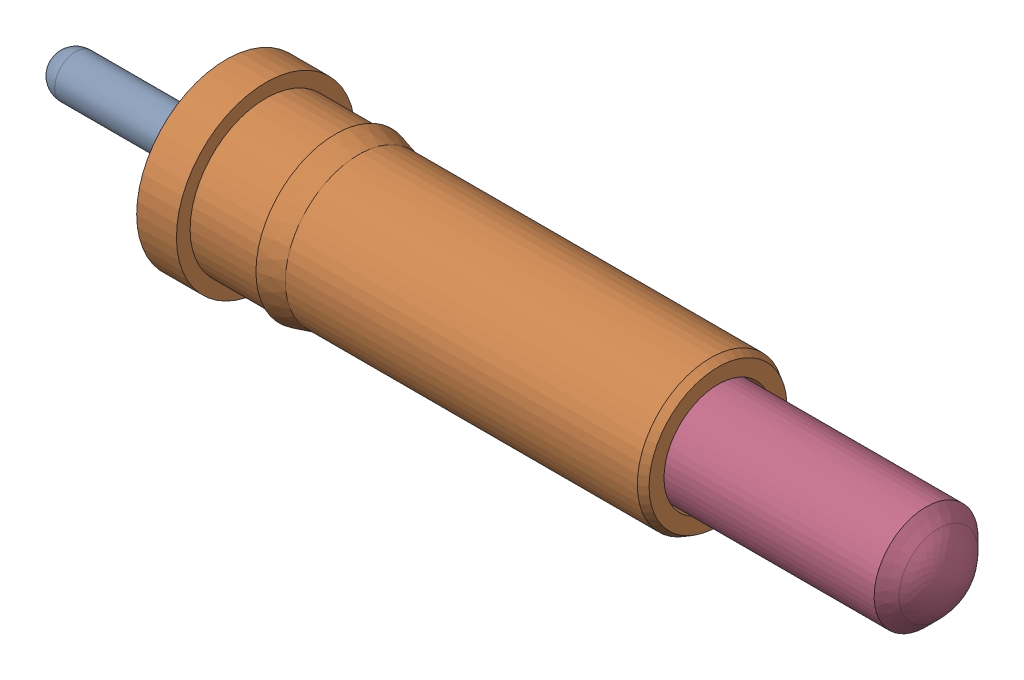
SolidWorks assembly mill-max-0908-2-15-20-75-14-11-0_1, configuration Default. Lengths in mm.
Overall size (9.22 1.83 1.83).
4 component instances, 4 part files, 0 mates.
Components (placement in the parent):
- mill-max-0908-2-15-20-75-14-11-0_0963-0_0963-0-00-20-00-00-13-0-1: mill-max-0908-2-15-20-75-14-11-0_0963-0_0963-0-00-20-00-00-13-0 [Default] at (0.1795 -0.8235 -1.1087) size (4.04 1.31 1.31)
- mill-max-0908-2-15-20-75-14-11-0_0954-0_0954-0-00-20-00-00-13-0-1: mill-max-0908-2-15-20-75-14-11-0_0954-0_0954-0-00-20-00-00-13-0 [Default] at (1.9321 -0.8235 -1.1087) size (5.03 1.83 1.83)
- mill-max-0908-2-15-20-75-14-11-0_SPRING_0975-0-00-00-75-14-45-0-1: mill-max-0908-2-15-20-75-14-11-0_SPRING_0975-0-00-00-75-14-45-0 [Default] at (5.5978 -0.8235 -1.1087) x (0 -0.998082 0.061903) z (-1 0 0) size (0.8 0.8 3.43)
- mill-max-0908-2-15-20-75-14-11-0_0918-X_0918-7-00-20-00-00-13-0-1: mill-max-0908-2-15-20-75-14-11-0_0918-X_0918-7-00-20-00-00-13-0 [Default] at (3.9133 -0.8235 -1.1087) x (1 0 0) z (0 0.540629 0.841261) size (5.49 1.25 1.25)
